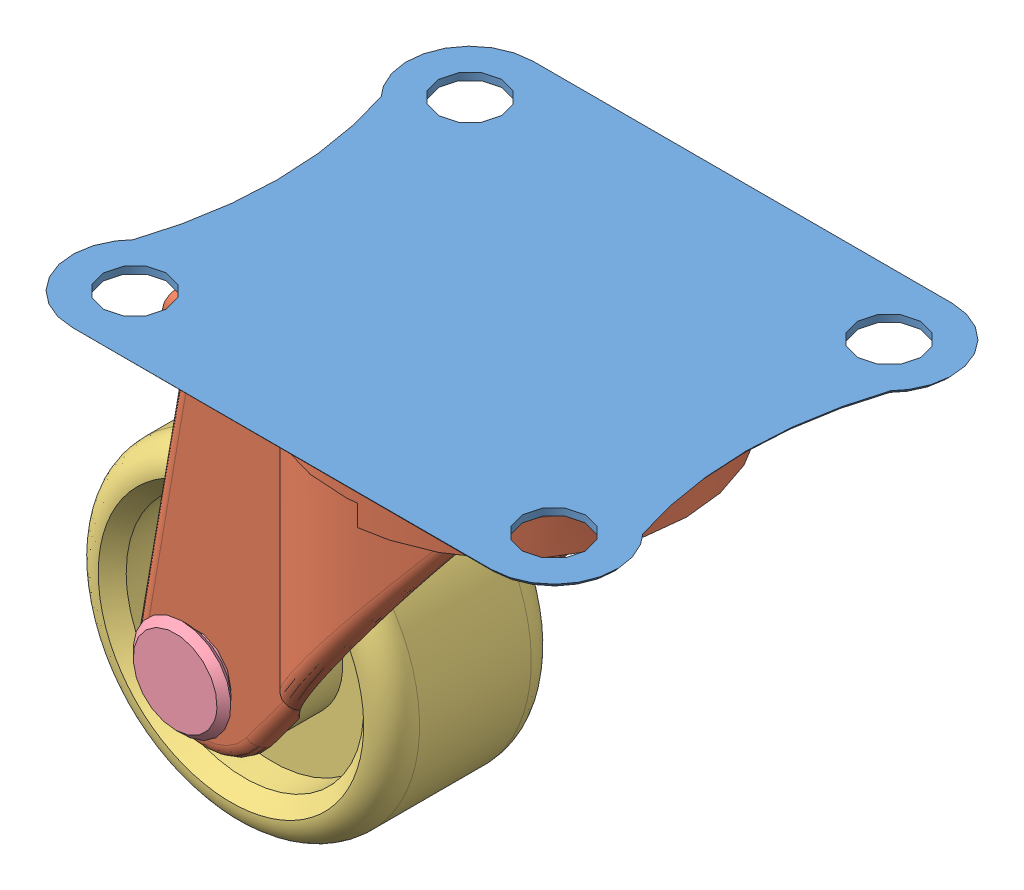
SolidWorks assembly Caster Wheel, configuration Default. Lengths in mm.
Overall size (45.94 37.59 33).
4 component instances, 4 part files, 6 mates.
Components (placement in the parent):
- caster holder-1: caster holder [Default] at (-24.0751 44.7184 29.5137) x (1 0 0) z (0 0 -1) size (39 9.27 33)
- holder-1: holder [Default] at (-1.5751 42.9484 46.0137) x (0 0 1) z (1 0 0) size (25 28.07 31.31)
- caster wheel-1: caster wheel [Default] at (-15.6961 19.9484 46.0137) x (0.997275 0.073773 0) z (0 0 1) size (23 23 14)
- Part4-1: Part4 [Default] at (-15.6961 19.9484 55.0137) x (-0.978448 0.206495 0) z (0 0 -1) size (7 7 20)
Mates (geometry in assembly coordinates):
- Coincident1: coincident: plane of caster holder-1 through (-1.5751 42.9484 46.0137) normal (0 -1 0); plane of holder-1 through (-1.5751 42.9484 46.0137) normal (0 1 0)
- Concentric2: concentric: cylinder of caster wheel-1 through (-15.6961 19.9484 39.0137) axis (0 0 1) radius 3.5; cylinder of holder-1 through (-15.6961 19.9484 33.5137) axis (0 0 1) radius 2.5
- Concentric3: concentric: cylinder of caster wheel-1 through (-15.6961 19.9484 39.0137) axis (0 0 1) radius 3.5; cylinder of Part4-1 through (-15.6961 19.9484 37.0137) axis (0 0 1) radius 2
- Concéntrica3: concentric: circle of caster holder-1; circle of holder-1
- Distancia3: distance = 0.5 mm: plane of holder-1 through (-24.6992 -15.0516 38.5137) normal (0 0 1); plane of caster wheel-1 through (-15.6961 19.9484 39.0137) normal (0 0 -1)
- Distancia4: distance = 0.5 mm: plane of holder-1 through (-9.6992 -15.0516 54.5137) normal (0 0 1); plane of Part4-1 through (-15.6961 19.9484 55.0137) normal (0 0 -1)
